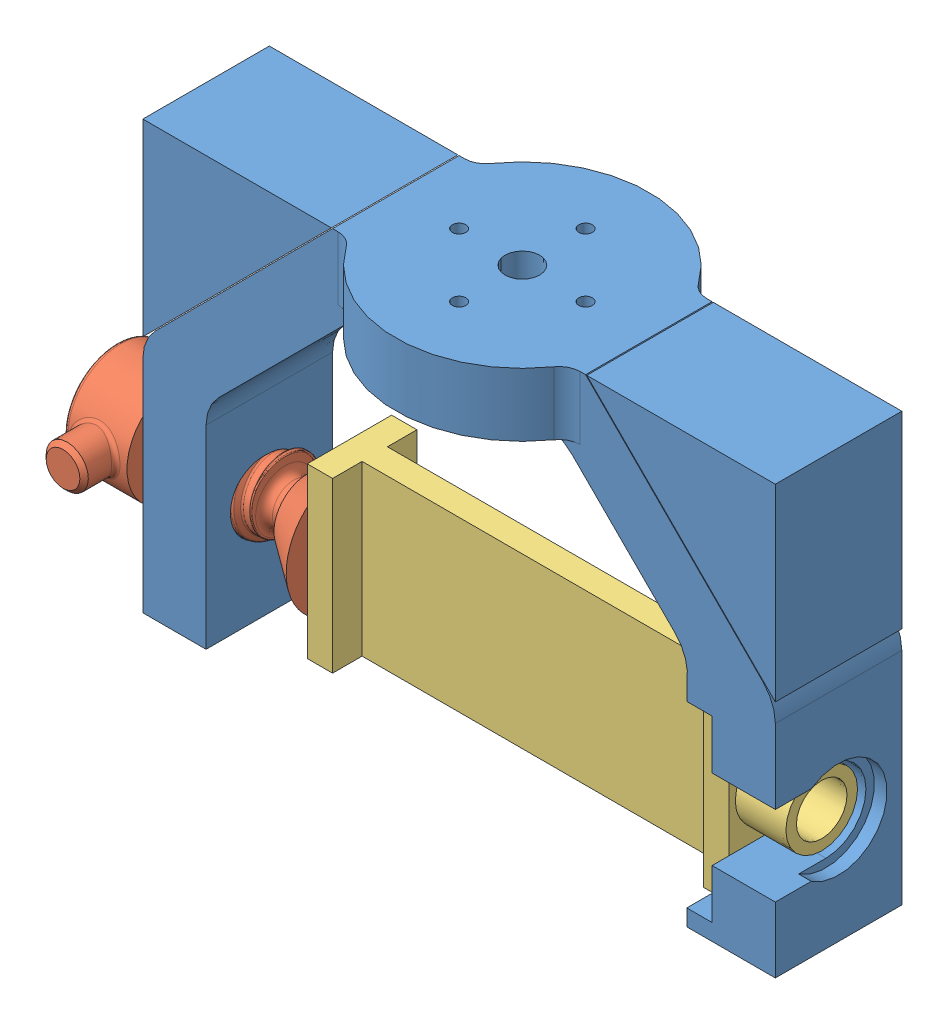
SolidWorks assembly Clamp Assembly_P, configuration Default. Lengths in mm.
Overall size (171.26 101.41 60).
7 component instances, 4 part files, 18 mates.
Components (placement in the parent):
- Clamp_Mount_P-1: Clamp_Mount_P [Default] at (-15.0821 73.1385 124.1314) size (150.29 101.41 60)
- Clamp_Rail_P-1: Clamp_Rail_P [Default] at (-96.3464 73.1385 139.1314) x (0 1 0) z (-1 0 0) size (30 40 55.26)
- I-Beam_Heat_Pipe_P-1: I-Beam_Heat_Pipe_P [Default] at (-56.0821 53.1385 149.1314) size (112 40 33.2)
- M3 x 0.5 Hex Nut-1: M3 x 0.5 Hex Nut [90592A085] at (-15.0821 143.7517 154.1314) x (0.866025 0 0.5) z (0.5 0 -0.866025) size (5.5 2.98 6.35)
- M3 x 0.5 Hex Nut-2: M3 x 0.5 Hex Nut [90592A085] at (-15.0821 143.7517 124.1314) x (-0.866025 0 0.5) z (0.5 0 0.866025) size (5.5 2.98 6.35)
- M3 x 0.5 Hex Nut-3: M3 x 0.5 Hex Nut [90592A085] at (-30.0821 143.7517 139.1314) x (-0.5 0 0.866025) z (0.866025 0 0.5) size (5.5 2.98 6.35)
- M3 x 0.5 Hex Nut-4: M3 x 0.5 Hex Nut [90592A085] at (-0.0821 143.7517 139.1314) x (-0.5 0 -0.866025) z (-0.866025 0 0.5) size (5.5 2.98 6.35)
Mates (geometry in assembly coordinates):
- Concentric1: concentric aligned: circle of Clamp_Mount-1; circle of M3 x 0.5 Hex Nut-1
- Parallel1: parallel anti-aligned: plane of Clamp_Mount-1 through (-16.7275 158.1586 151.2814) normal (0 0 1); plane of M3 x 0.5 Hex Nut-1 through (-16.6698 142.5517 151.3814) normal (0 0 -1)
- Coincident2: coincident anti-aligned: plane of Clamp_Mount-1 through (-45.0821 144.9517 154.1314) normal (0 -1 0); plane of M3 x 0.5 Hex Nut-1 through (-18.2575 144.9517 154.1314) normal (0 1 0)
- Concentric2: concentric aligned: circle of Clamp_Mount-1; circle of M3 x 0.5 Hex Nut-2
- Parallel2: parallel anti-aligned: plane of Clamp_Mount-1 through (-13.4366 158.1586 121.2814) normal (-0.866025 0 0.5); plane of M3 x 0.5 Hex Nut-2 through (-13.4944 142.5517 121.3814) normal (0.866025 0 -0.5)
- Coincident4: coincident anti-aligned: plane of Clamp_Mount-1 through (-45.0821 144.9517 154.1314) normal (0 -1 0); plane of M3 x 0.5 Hex Nut-2 through (-13.4944 144.9517 121.3814) normal (0 1 0)
- Concentric3: concentric aligned: circle of Clamp_Mount-1; circle of M3 x 0.5 Hex Nut-4
- Coincident5: coincident anti-aligned: plane of Clamp_Mount-1 through (-45.0821 144.9517 154.1314) normal (0 -1 0); plane of M3 x 0.5 Hex Nut-4 through (2.6679 144.9517 140.7192) normal (0 1 0)
- Parallel3: parallel anti-aligned: plane of Clamp_Mount-1 through (2.7679 158.1586 137.486) normal (-1 0 0); plane of M3 x 0.5 Hex Nut-4 through (2.6679 142.5517 137.5437) normal (1 0 0)
- Concentric4: concentric aligned: circle of Clamp_Mount-1; circle of M3 x 0.5 Hex Nut-3
- Parallel4: parallel anti-aligned: plane of Clamp_Mount-1 through (-27.2321 158.1586 137.486) normal (-1 0 0); plane of M3 x 0.5 Hex Nut-3 through (-27.3321 142.5517 137.5437) normal (1 0 0)
- Coincident8: coincident anti-aligned: plane of Clamp_Mount-1 through (-45.0821 144.9517 154.1314) normal (0 -1 0); plane of M3 x 0.5 Hex Nut-3 through (-30.0821 144.9517 135.956) normal (0 1 0)
- Concentric6: concentric anti-aligned: circle of Clamp_Mount-1; circle of I-Beam_Heat_Pipe_P-1
- Distance1: distance = 1 mm anti-aligned: plane of I-Beam_Heat_Pipe_P-1 through (43.9179 93.1385 129.1314) normal (1 0 0); plane of Clamp_Mount-1 through (44.9179 48.0385 154.1314) normal (-1 0 0)
- Parallel6: parallel anti-aligned: plane of Clamp_Mount-1 through (38.9179 94.3385 154.1314) normal (0 -1 0); plane of I-Beam_Heat_Pipe_P-1 through (-56.0821 93.1385 149.1314) normal (0 1 0)
- Coincident12: coincident anti-aligned: plane of Clamp_Rail-1 through (-56.0821 73.1385 139.1314) normal (1 0 0); plane of I-Beam_Heat_Pipe_P-1 through (-56.0821 93.1385 149.1314) normal (-1 0 0)
- Concentric7: concentric anti-aligned: circle of Clamp_Rail-1; circle of I-Beam_Heat_Pipe_P-1
- Parallel7: parallel aligned: plane of Clamp_Mount-1 through (-15.0821 73.1385 154.1314) normal (0 0 1); plane of Clamp_Rail-1 through (-104.0066 73.1385 159.1314) normal (0 0 1)
